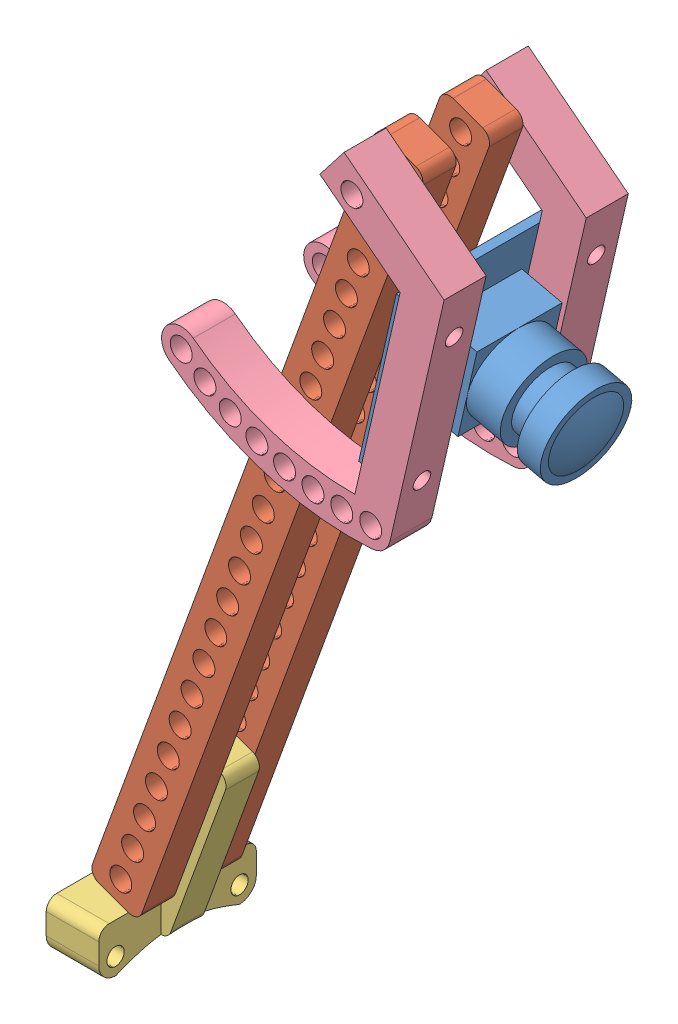
SolidWorks assembly cameraAssem, configuration Default. Lengths in mm.
Overall size (93.92 163.2 35.05).
6 component instances, 4 part files, 17 mates.
Components (placement in the parent):
- camera-1: camera [Default] at (39.4581 42.1475 -4.825) x (-0.223464 -0.974712 0) z (0 0 1) size (32 25.81 32)
- cameraArm-1: cameraArm [Default] at (9.9392 -0.2097 -14.525) x (0.939693 -0.34202 0) z (0 0 1) size (10 160 6.35)
- cameraArmBlock-1: cameraArmBlock [Default] at (-24.7699 -82.5675 -5) size (22.41 38.19 30)
- cameraArm-2: cameraArm [Default] at (9.9392 -0.2097 -1.825) x (0.939693 -0.34202 0) z (0 0 1) size (10 160 6.35)
- cameraMount-1: cameraMount [Default] at (-10.766 11.2468 -14.525) x (-0.78895 0.614458 0) z (0 0 -1) size (43.99 60.62 8)
- cameraMount-2: cameraMount [Default] at (-10.766 11.2468 12.525) x (-0.78895 0.614458 0) z (0 0 -1) size (43.99 60.62 8)
Mates (geometry in assembly coordinates):
- Concentric2: concentric aligned: cylinder of cameraArm-1 through (35.9328 71.2069 -8.175) axis (0 0 -1) radius 2.1; cylinder of cameraArm-2 through (35.9328 71.2069 4.525) axis (0 0 -1) radius 2.1
- Coincident3: coincident aligned: plane of cameraArm-1 through (40.1199 73.9396 -8.175) normal (0.34202 0.939693 0); plane of cameraArm-2 through (40.1199 73.9396 4.525) normal (0.34202 0.939693 0)
- Coincident4: coincident anti-aligned: plane of cameraArmBlock-1 through (-12.818 -49.5774 -1.825) normal (0 0 1); plane of cameraArm-2 through (-19.5574 -72.4797 -1.825) normal (0 0 -1)
- Concentric3: concentric aligned: cylinder of cameraArmBlock-1 through (-9.2734 -52.9959 -1.825) axis (0 0 -1) radius 2.1; cylinder of cameraArm-2 through (-9.2734 -52.9959 4.525) axis (0 0 -1) radius 2.1
- Concentric11: concentric: cylinder of cameraArmBlock-1 through (-13.7949 -65.4187 -1.825) axis (0 0 -1) radius 2.1; cylinder of cameraArm-2 through (-13.794 -65.4162 4.525) axis (0 0 -1) radius 2.1
- Parallel1: parallel aligned: cylinder of cameraArmBlock-1 through (-16.0556 -71.63 -1.825) axis (0 0 -1) radius 2.1; cylinder of cameraArm-2 through (-16.0543 -71.6263 4.525) axis (0 0 -1) radius 2.1
- Parallel2: parallel aligned: cylinder of cameraArm-1 through (-16.0543 -71.6263 -8.175) axis (0 0 -1) radius 2.1; cylinder of cameraArmBlock-1 through (-16.0556 -71.63 -1.825) axis (0 0 -1) radius 2.1
- Parallel4: parallel aligned: cylinder of cameraArmBlock-1 through (-11.5341 -59.2073 -1.825) axis (0 0 -1) radius 2.1; cylinder of cameraArm-2 through (-11.5337 -59.2061 4.525) axis (0 0 -1) radius 2.1
- Coincident5: coincident anti-aligned: plane of cameraArm-1 through (-19.5574 -72.4797 -8.175) normal (0 0 1); plane of cameraArmBlock-1 through (-12.818 -49.5774 -8.175) normal (0 0 -1)
- Concentric12: concentric anti-aligned: cylinder of cameraArm-1 through (35.9328 71.2069 -8.175) axis (0 0 -1) radius 2.1; cylinder of cameraMount-1 through (35.9328 71.2069 -22.525) axis (0 0 1) radius 2.1
- Coincident9: coincident anti-aligned: plane of cameraArm-1 through (-19.5574 -72.4797 -14.525) normal (0 0 -1); plane of cameraMount-1 through (-10.766 11.2468 -14.525) normal (0 0 1)
- Coincident11: coincident anti-aligned: plane of camera-1 through (41.0177 41.7899 -4.825) normal (0.974712 -0.223464 0); plane of cameraMount-1 through (31.7791 1.4928 -22.525) normal (-0.974712 0.223464 0)
- Concentric13: concentric anti-aligned: cylinder of cameraArm-2 through (35.9328 71.2069 4.525) axis (0 0 -1) radius 2.1; cylinder of cameraMount-2 through (35.9328 71.2069 4.525) axis (0 0 1) radius 2.1
- Coincident13: coincident anti-aligned: plane of cameraArm-2 through (-19.5574 -72.4797 4.525) normal (0 0 1); plane of cameraMount-2 through (-10.766 11.2468 4.525) normal (0 0 -1)
- Coincident14: coincident aligned: plane of cameraMount-1 through (39.0894 -0.1832 -22.525) normal (0.974712 -0.223464 0); plane of cameraMount-2 through (39.0894 -0.1832 4.525) normal (0.974712 -0.223464 0)
- Concentric14: concentric anti-aligned: cylinder of camera-1 through (44.0791 55.1435 -18.525) axis (-0.974712 0.223464 0) radius 1.3; cylinder of cameraMount-1 through (5.0991 64.0801 -18.525) axis (0.974712 -0.223464 0) radius 1.65
- Concentric15: concentric anti-aligned: cylinder of camera-1 through (37.9562 28.4364 -18.525) axis (-0.974712 0.223464 0) radius 1.3; cylinder of cameraMount-1 through (-1.0238 37.3729 -18.525) axis (0.974712 -0.223464 0) radius 1.65
